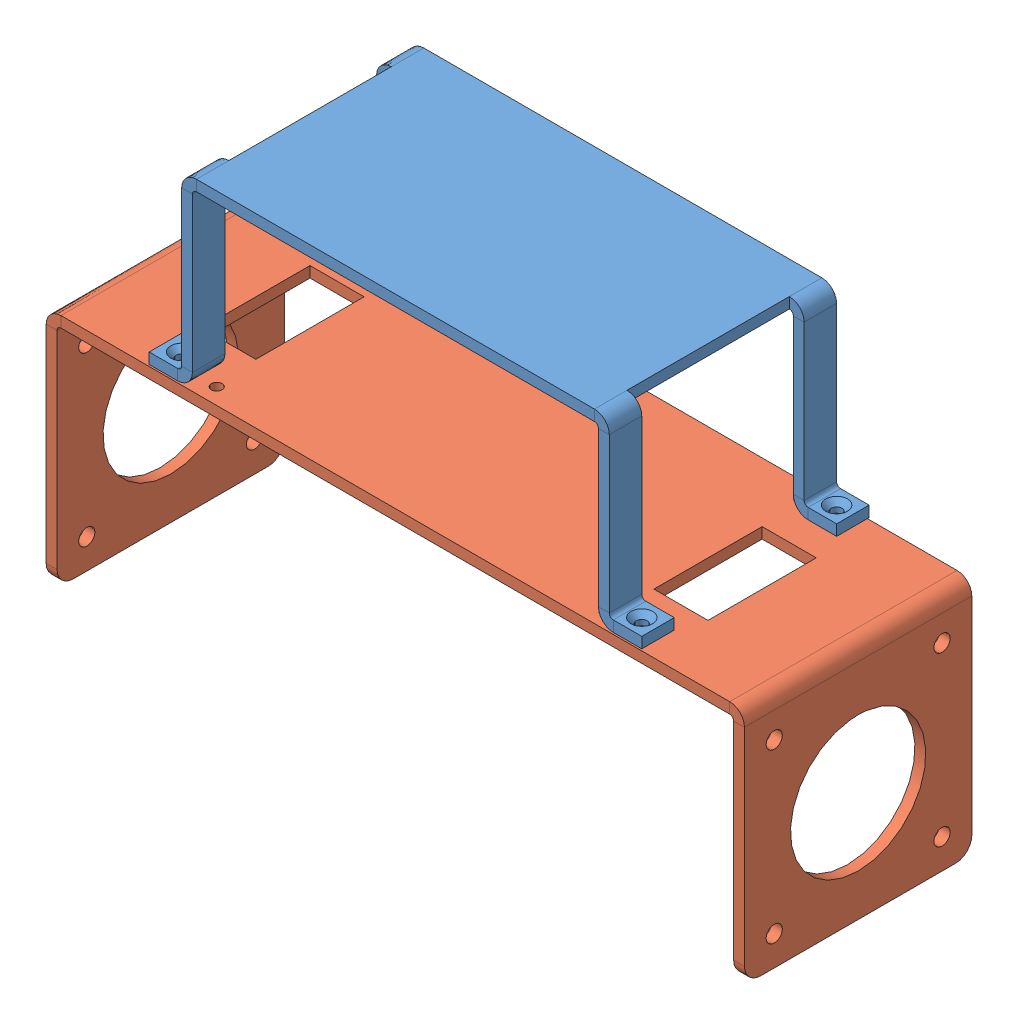
SolidWorks assembly 平衡小车, configuration 默认. Lengths in mm.
Overall size (129 78.29 42.03).
2 component instances, 2 part files, 0 mates.
Components (placement in the parent):
- 车盖-1: 车盖 [默认] at (-19.7936 -5.2988 -5.9736) size (91 34 42)
- 车架-1: 车架 [默认] at (-3.9658 -39.5931 -7.335) size (129 44 42)
